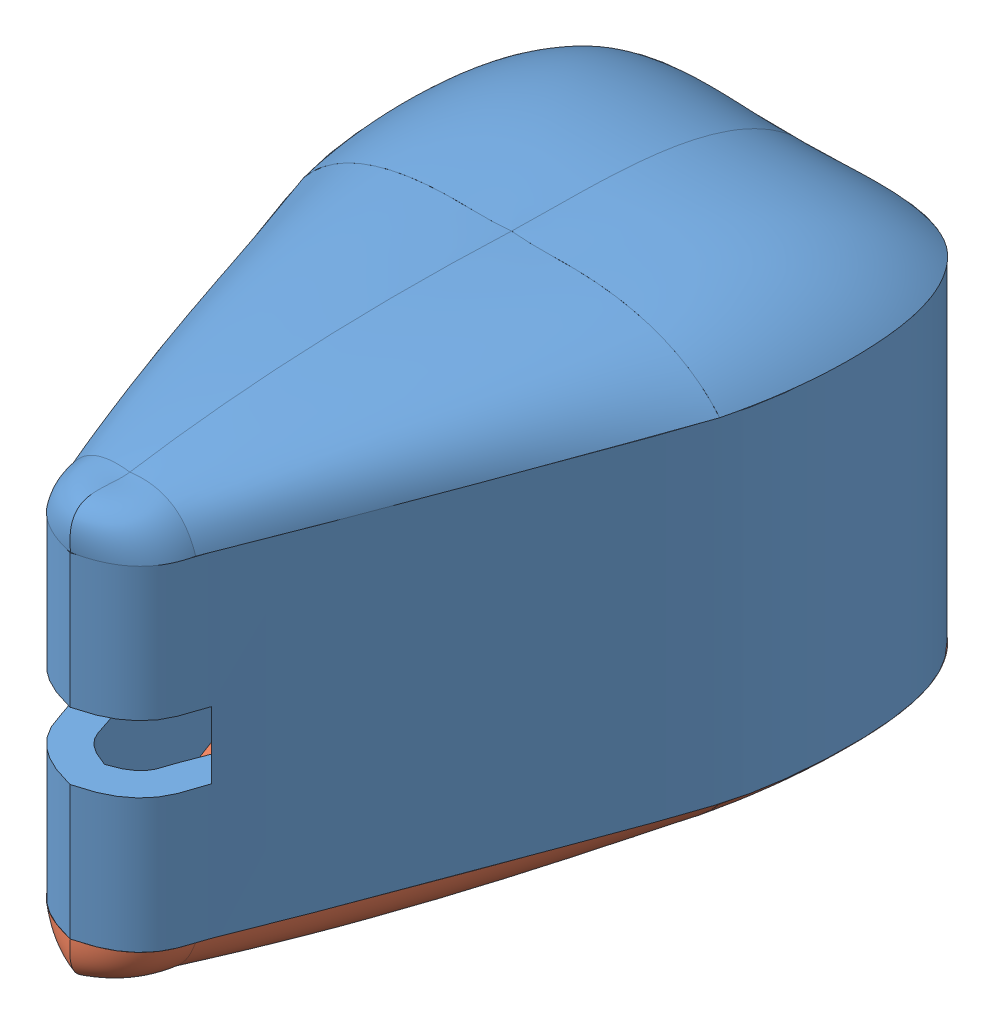
SolidWorks assembly headassembly, configuration Default. Lengths in mm.
Overall size (17.37 17.35 27.84).
2 component instances, 2 part files, 3 mates.
Components (placement in the parent):
- headpart2shaun-1: headpart2shaun [Default] at (-9.0335 20.5653 27.5056) size (17.35 15.42 27.83)
- headpart1shaun-1: headpart1shaun [Default] at (-9.0346 7.8653 27.5056) x (-1 0 -0.000469) z (-0.000469 0 1) size (17.35 5.37 27.83)
Mates (geometry in assembly coordinates):
- Concentric1: concentric: cylinder of headpart2shaun-1 through (-9.0335 20.8193 25.0056) axis (0 -1 0) radius 1.5031; cylinder of headpart1shaun-1 through (-9.0335 10.9133 25.0056) axis (0 -1 0) radius 1.5031
- Coincident1: coincident: plane of headpart2shaun-1 through (-16.6253 7.8653 25.9067) normal (0 -1 0); plane of headpart1shaun-1 through (-6.5402 7.8653 39.5068) normal (0 1 0)
- Tangent2: tangent: curve of headpart2shaun-1; curve of headpart1shaun-1
